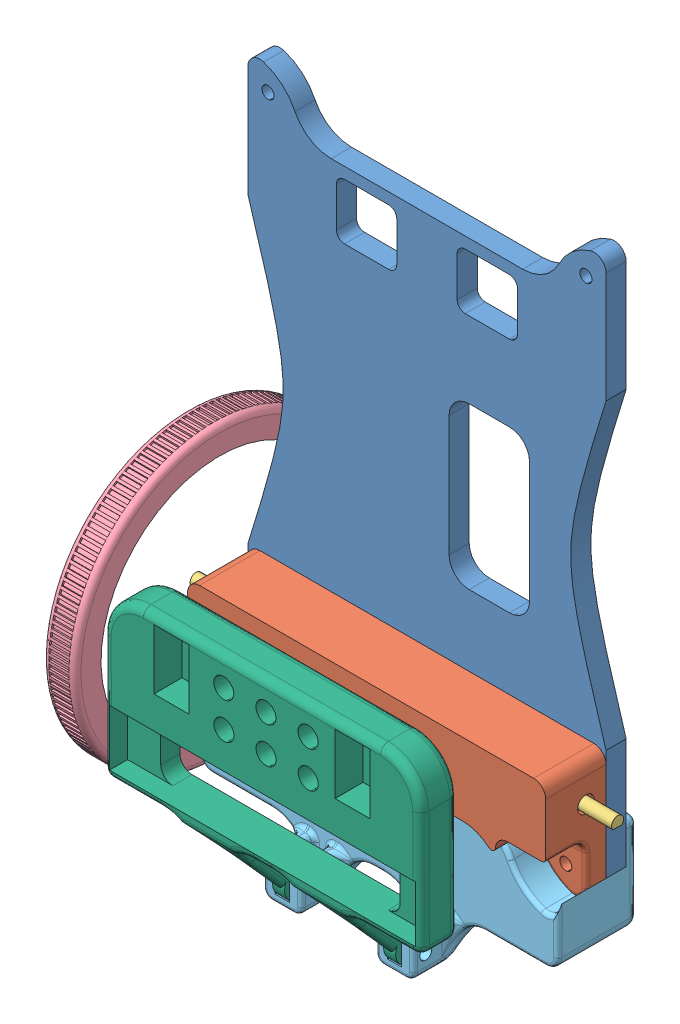
SolidWorks assembly Montagem, configuration Valor predeterminado. Lengths in mm.
Overall size (106.87 163.58 97.49).
9 component instances, 7 part files, 17 mates.
Components (placement in the parent):
- chassi-1: chassi [Valor predeterminado] at (23.4572 -41.9098 -2.5) size (89 136.28 5)
- suporte motor-1: suporte motor [Valor predeterminado] at (7.3294 33.688 2.5) x (-1 0 0) z (0 0 1) size (89 30.54 15)
- Pololu #2218 Micro Metal Gearmotor HP-1: Pololu #2218 Micro Metal Gearmotor HP [Valor predeterminado] at (48.8933 -50.8109 7.5) x (0 0 -1) z (-1 0 0) size (10 12 35.52)
- Pololu #2218 Micro Metal Gearmotor HP-2: Pololu #2218 Micro Metal Gearmotor HP [Valor predeterminado] at (-18.1067 -50.8109 7.5) x (0 0 1) z (1 0 0) size (10 12 35.52)
- Roda-70mm-1: Roda-70mm [Valor predeterminado] at (-31.1067 -50.8109 7.5) x (0 0.476407 0.879225) z (-1 0 0) size (71.92 71.92 8)
  - pololu wheel 70x8mm ref.14251-1: pololu wheel 70x8mm ref.14251 [Valor predeterminado] at origin (suppressed, hidden)
  - pololu wheel 70x8mm ref.14252-1: pololu wheel 70x8mm ref.14252 [Valor predeterminado] at origin size (71.92 71.92 8)
- SuporteDoArraynovonovonew-1: SuporteDoArraynovonovonew [Valor predeterminado] at (-0.7051 -59.7752 -2.5) x (0 0 1) z (1 0 0) size (30 34.04 89)
- Peça5-1: Peça5 [Valor predeterminado] at (3.0133 -87.8727 20.0725) x (0 0.999992 0.003952) z (-1 0 0) size (65 25.86 78.95)
Mates (geometry in assembly coordinates):
- Concêntrico3: concentric aligned: circle of suporte motor-1; circle of Pololu #2218 Micro Metal Gearmotor HP-2
- Coincidente3: coincident anti-aligned: plane of suporte motor-1 through (-27.1067 -55.9109 12.6) normal (1 0 0); plane of Pololu #2218 Micro Metal Gearmotor HP-2 through (-27.1067 -54.6609 4.65) normal (-1 0 0)
- Concêntrico4: concentric aligned: circle of suporte motor-1; circle of Pololu #2218 Micro Metal Gearmotor HP-1
- Coincidente4: coincident anti-aligned: plane of suporte motor-1 through (57.8933 -55.9109 12.6) normal (-1 0 0); plane of Pololu #2218 Micro Metal Gearmotor HP-1 through (57.8933 -54.6609 10.35) normal (1 0 0)
- Coincidente5: coincident anti-aligned: plane of chassi-1 through (51.1131 -4.1109 2.5) normal (0 0 1); plane of suporte motor-1 through (56.8933 -44.7109 2.5) normal (0 0 -1)
- Concêntrico5: concentric aligned: circle of chassi-1; circle of suporte motor-1
- Concêntrico6: concentric aligned: circle of chassi-1; circle of suporte motor-1
- Concêntrico7: concentric anti-aligned: circle of Pololu #2218 Micro Metal Gearmotor HP-2; circle of Roda-70mm-1/pololu wheel 70x8mm ref.14252-1
- Distância1: distance = 2 mm anti-aligned: plane of Roda-70mm-1/pololu wheel 70x8mm ref.14252-1 through (-31.1067 -65.3012 54.5538) normal (1 0 0); plane of suporte motor-1 through (-29.1067 -69.2503 17.5) normal (-1 0 0)
- Coincidente10: coincident anti-aligned: plane of chassi-1 through (51.1131 -4.1109 -2.5) normal (0 0 -1); plane of SuporteDoArraynovonovonew-1 through (56.8933 -43.0021 -2.5) normal (0 0 1)
- Concêntrico8: concentric aligned: circle of chassi-1; circle of SuporteDoArraynovonovonew-1
- Concêntrico9: concentric aligned: circle of suporte motor-1; circle of SuporteDoArraynovonovonew-1
- Distância2: distance = 0.01 mm: plane of Peça5-1 through (-0.2967 -68.7096 19.8239) normal (-1 0 0); plane of SuporteDoArraynovonovonew-1 through (-0.3067 -63.7521 27.5) normal (1 0 0)
- Concêntrico10: concentric: circle of SuporteDoArraynovonovonew-1; circle of Peça5-1
- Concêntrico11: concentric: circle of SuporteDoArraynovonovonew-1; circle of Peça5-1
- Concêntrico12: concentric anti-aligned: circle of SuporteDoArraynovonovonew-1; circle of Peça5-1
- Coincidente11: coincident anti-aligned: plane of SuporteDoArraynovonovonew-1 through (27.5933 -91.7521 -2.5) normal (1 0 0); plane of Peça5-1 through (27.5933 -87.8727 20.0725) normal (-1 0 0)
